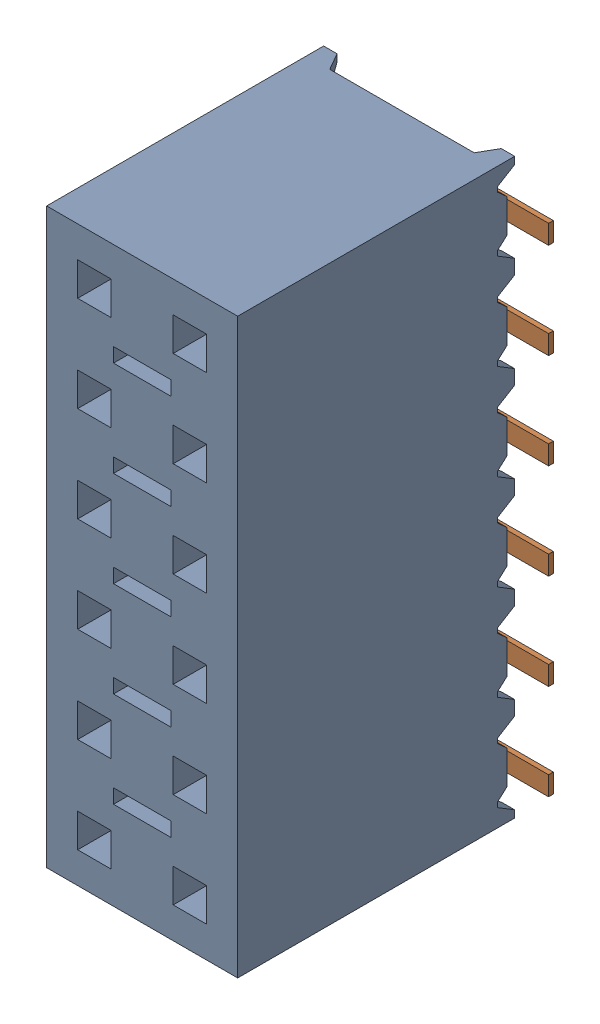
SolidWorks assembly P24.step, configuration Default. Lengths in mm.
Overall size (7.04 15.24 7.42).
3 component instances, 2 part files, 0 mates.
Components (placement in the parent):
- SSM-106-F-DV.step-1: SSM-106-F-DV.step [Default] at (95.2501 15.2399 0) x (0 -1 0) z (-1 0 0) size (15.24 7.42 7.04)
  - _SSM-106-F-DV_body.step-1: _SSM-106-F-DV_body.step [Default] at origin size (15.24 7.37 5.08)
  - _C-137-016.step-1: _C-137-016.step [Default] at (0 -0.0508 0) size (13.21 1.91 7.04)
